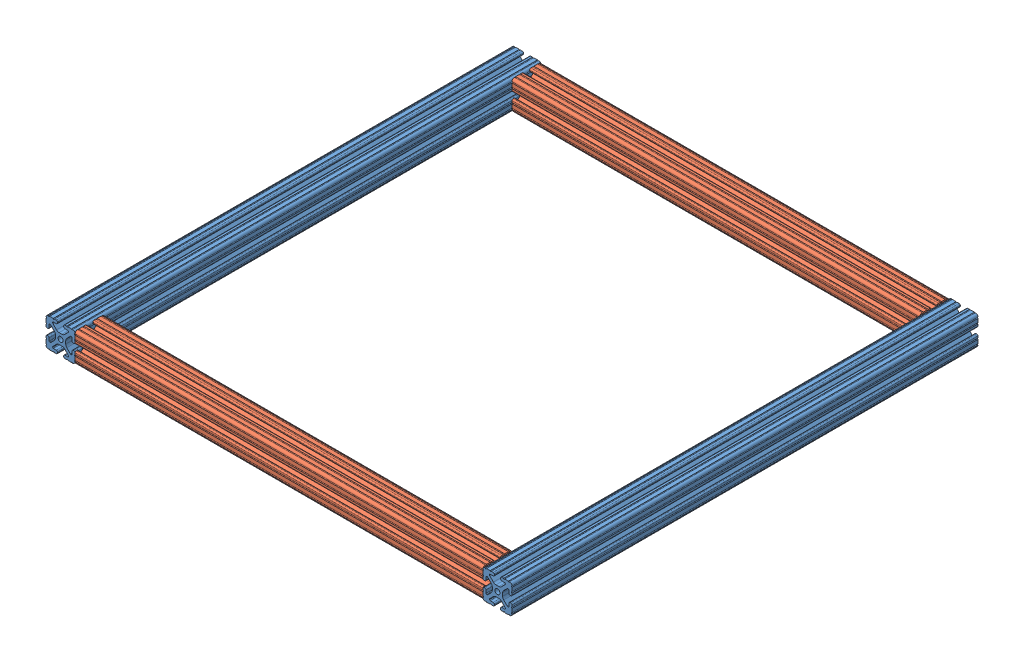
SolidWorks assembly Frame, configuration Default. Lengths in mm.
Overall size (609.6 38.1 609.6).
4 component instances, 2 part files, 9 mates.
Components (placement in the parent):
- T-Slot Top Long-1: T-Slot Top Long [47065T21] at (82.9387 391.4039 494.442) size (38.1 38.1 609.6)
- T-Slot Top Long-2: T-Slot Top Long [47065T21] at (654.4387 391.4039 494.442) size (38.1 38.1 609.6)
- T-Slot Top Short-1: T-Slot Top Short [47065T21] at (368.6887 391.4039 780.192) x (0 0 -1) z (1 0 0) size (38.1 38.1 533.4)
- T-Slot Top Short-2: T-Slot Top Short [47065T21] at (368.6887 391.4039 208.692) x (0 0 1) z (-1 0 0) size (38.1 38.1 533.4)
Mates (geometry in assembly coordinates):
- Coincident1: coincident anti-aligned: plane of T-Slot Top Long-1 through (101.9887 397.0215 799.242) normal (1 0 0); plane of T-Slot Top Short-1 through (101.9887 404.9563 789.5773) normal (-1 0 0)
- Coincident2: coincident aligned: plane of T-Slot Top Long-1 through (73.5534 404.9563 799.242) normal (0 0 1); plane of T-Slot Top Short-1 through (635.3887 399.3802 799.242) normal (0 0 1)
- Coincident3: coincident aligned: plane of T-Slot Top Long-1 through (90.9129 410.4539 799.242) normal (0 1 0); plane of T-Slot Top Short-1 through (635.3887 410.4539 785.8096) normal (0 1 0)
- Coincident4: coincident anti-aligned: plane of T-Slot Top Long-2 through (635.3887 399.3802 799.242) normal (-1 0 0); plane of T-Slot Top Short-1 through (635.3887 404.9563 789.5773) normal (1 0 0)
- Coincident5: coincident aligned: plane of T-Slot Top Long-2 through (645.0534 404.9563 799.242) normal (0 0 1); plane of T-Slot Top Short-1 through (635.3887 399.3802 799.242) normal (0 0 1)
- Coincident6: coincident aligned: plane of T-Slot Top Long-2 through (648.8211 410.4539 799.242) normal (0 1 0); plane of T-Slot Top Short-1 through (635.3887 410.4539 785.8096) normal (0 1 0)
- Coincident7: coincident anti-aligned: plane of T-Slot Top Long-1 through (101.9887 397.0215 799.242) normal (1 0 0); plane of T-Slot Top Short-2 through (101.9887 404.9563 199.3067) normal (-1 0 0)
- Coincident8: coincident aligned: plane of T-Slot Top Long-1 through (90.9129 410.4539 799.242) normal (0 1 0); plane of T-Slot Top Short-2 through (101.9887 410.4539 203.0743) normal (0 1 0)
- Coincident9: coincident aligned: plane of T-Slot Top Long-1 through (73.5534 404.9563 189.642) normal (0 0 -1); plane of T-Slot Top Short-2 through (101.9887 385.7863 189.642) normal (0 0 -1)
